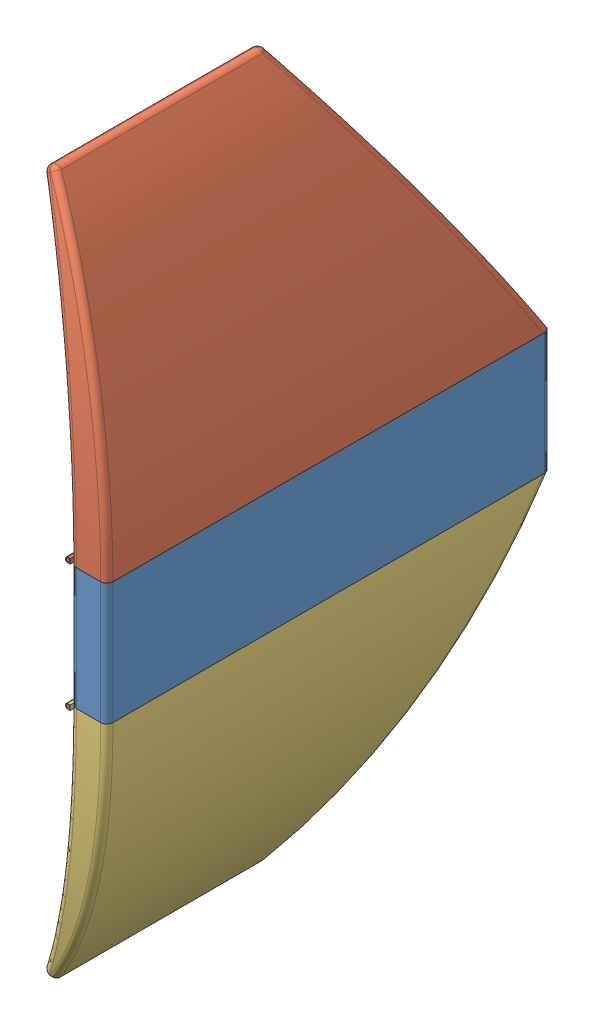
SolidWorks assembly Wing Subassembly, configuration Default. Lengths in mm.
Overall size (6.34 28.86 19.17).
5 component instances, 4 part files, 9 mates.
Components (placement in the parent):
- Tie Wing Attachment-1: Tie Wing Attachment [Default] at (6.4824 6.7469 4.9672) size (2.1 5.4 18.2)
- Tie Wing 1-1: Tie Wing 1 [Default] at (6.4826 11.7469 23.1672) size (6.34 11.93 19.16)
- Tie Wing 2-1: Tie Wing 2 [Default] at (6.4824 6.7469 4.9672) x (1 0 0) z (0 0 -1) size (6.29 11.93 19.17)
- Wing Attachment Rod-1: Wing Attachment Rod [Default] at (6.3824 11.8469 5.1672) x (0 0 1) z (-0.451392 -0.892326 0) size (18 0.12 0.12)
- Wing Attachment Rod-2: Wing Attachment Rod [Default] at (6.3824 6.6469 23.1672) x (0 0 -1) z (1 0 0) size (18 0.12 0.12)
Mates (geometry in assembly coordinates):
- DUMMY - WING LOCKED: coincident anti-aligned: plane of Tie Wing Attachment-1 through (7.9824 6.7469 23.1672) normal (0 -1 0); plane of Tie Wing 2-1 through (6.4824 6.7469 23.0672) normal (0 1 0)
- LimitAngle2: limit planar angle = 0 rad anti-aligned: plane of Tie Wing Attachment-1 through (7.9824 11.7469 4.9672) normal (0 1 0); plane of Tie Wing 1-1 through (2.2837 11.7469 12.6672) normal (0 -1 0)
- Hinge2: hinge anti-aligned: circle of Tie Wing 2-1; circle of Tie Wing Attachment-1; plane of Tie Wing 2-1 through (6.3824 6.6469 12.6672) normal (0 0 1); plane of Tie Wing Attachment-1 through (6.2824 7.1469 12.6672) normal (0 0 -1)
- LimitAngle3: limit planar angle = 0 rad anti-aligned: plane of Tie Wing Attachment-1 through (7.9824 6.7469 23.1672) normal (0 -1 0); plane of Tie Wing 2-1 through (6.4824 6.7469 23.1672) normal (0 1 0)
- Hinge3: hinge anti-aligned: circle of Tie Wing 1-1; circle of Tie Wing Attachment-1; plane of Tie Wing Attachment-1 through (6.2824 11.3469 12.6672) normal (0 0 -1); plane of Tie Wing 1-1 through (6.3824 11.8469 12.6672) normal (0 0 1)
- Concentric1: concentric anti-aligned: cylinder of Tie Wing 1-1 through (6.3824 11.8469 4.9672) axis (0 0 1) radius 0.06; cylinder of Wing Attachment Rod-1 through (6.3824 11.8469 23.1672) axis (0 0 -1) radius 0.06
- Coincident1: coincident aligned: plane of Tie Wing 1-1 through (2.2837 11.9469 23.1672) normal (0 0 1); plane of Wing Attachment Rod-1 through (6.3824 11.8469 23.1672) normal (0 0 1)
- Concentric2: concentric anti-aligned: cylinder of Tie Wing 2-1 through (6.3824 6.6469 23.1672) axis (0 0 -1) radius 0.06; cylinder of Wing Attachment Rod-2 through (6.3824 6.6469 5.1672) axis (0 0 1) radius 0.06
- Tangent1: tangent aligned: cylinder of Tie Wing 2-1 through (7.9834 6.7469 -16.8328) axis (-1 0 0) radius 40; plane of Wing Attachment Rod-2 through (6.3824 6.6469 23.1672) normal (0 0 1)
